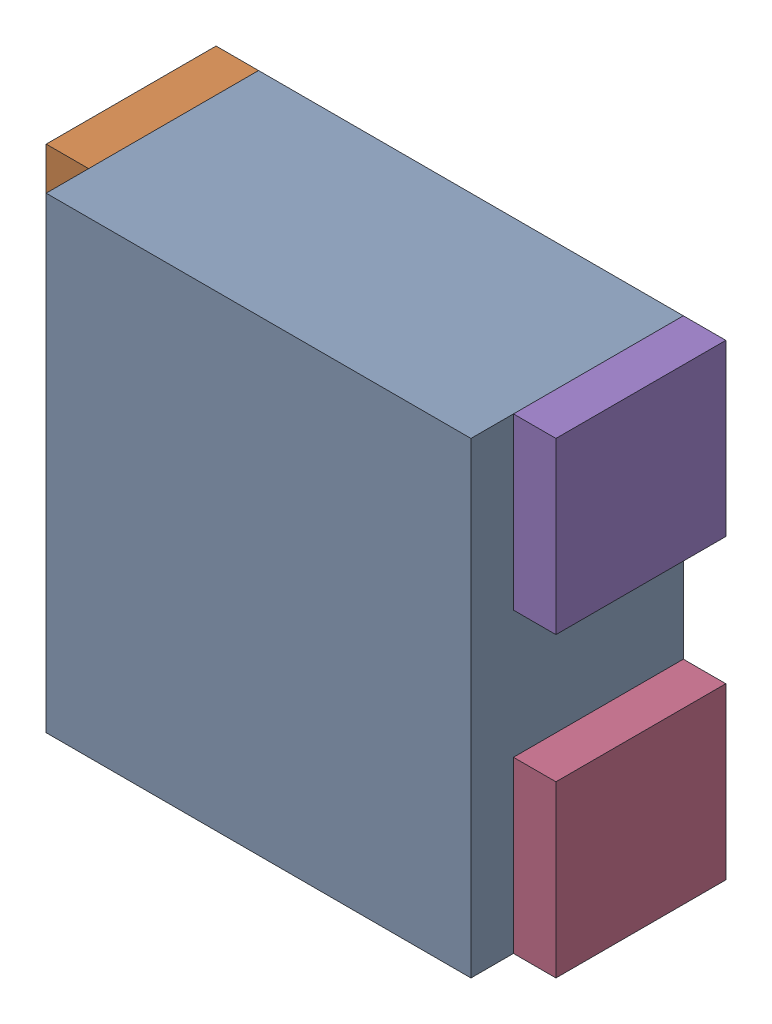
SolidWorks assembly RN26, configuration Default. Lengths in mm.
Overall size (1.2 1.1 0.5).
10 component instances, 2 part files, 0 mates.
Components (placement in the parent):
- 836749552-1: 836749552 [Default] at (108.05 16.25 0) size (1 1.1 0.5)
  - Extruded_11-1: Extruded_11 [Default] at origin size (1 1.1 0.5)
- 791587232-1: 791587232 [Default] at (107.5 16.6 0) size (0.1 0.4 0.4)
  - Extruded_10-1: Extruded_10 [Default] at origin size (0.1 0.4 0.4)
- 791587232-2: 791587232 [Default] at (107.5 15.9 0) size (0.1 0.4 0.4)
  - Extruded_10-1: Extruded_10 [Default] at origin size (0.1 0.4 0.4)
- 791587232-3: 791587232 [Default] at (108.6 15.9 0) size (0.1 0.4 0.4)
  - Extruded_10-1: Extruded_10 [Default] at origin size (0.1 0.4 0.4)
- 791587232-4: 791587232 [Default] at (108.6 16.6 0) size (0.1 0.4 0.4)
  - Extruded_10-1: Extruded_10 [Default] at origin size (0.1 0.4 0.4)
